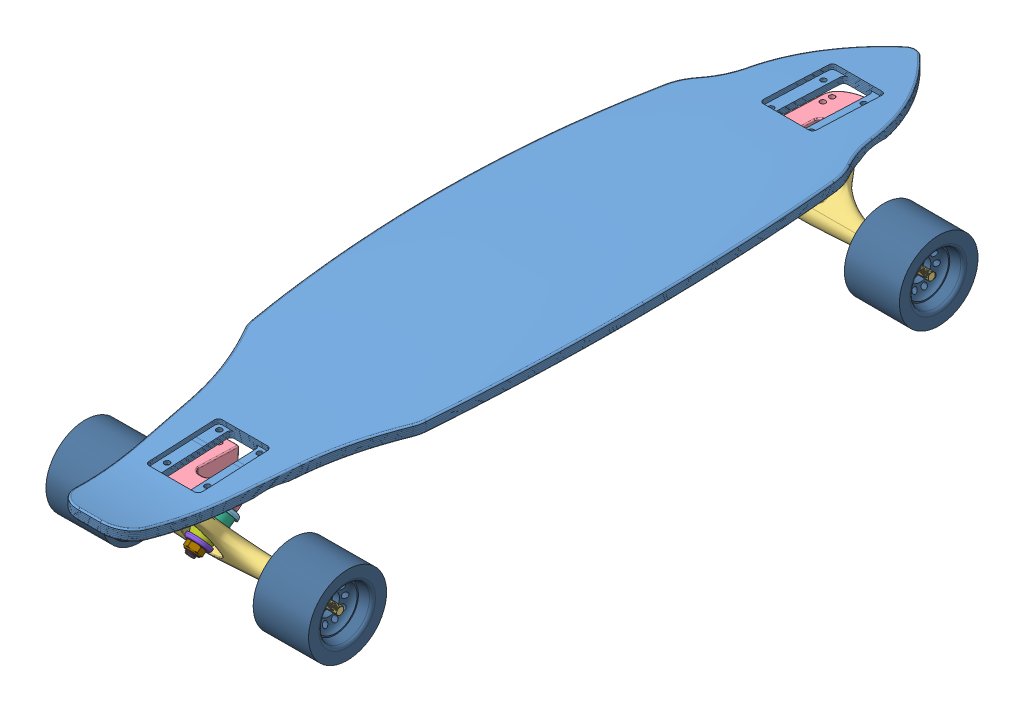
SolidWorks assembly DeckAndTrucks, configuration Default. Lengths in mm.
Overall size (266.41 157.6 846.49).
25 component instances, 11 part files, 25 mates.
Components (placement in the parent):
- Chamber Deck-2: Chamber Deck [Default] at origin size (203.4 42.87 846.49)
- Truck Cutout-1: Truck Cutout [Default] at (0 15.4335 -251.2196) x (-1 0 0) z (0 0.040365 0.999185) size (652.75 200 200) (hidden)
- Truck Cutout-2: Truck Cutout [Default] at (0 12.2172 374.2126) x (1 0 0) z (0 0.044825 -0.998995) size (652.75 200 200) (hidden)
- Truck-2: Truck [Default] at (27.686 -6.6481 -210.3024) x (1 0 0) z (0 -0.0403 -0.999188) size (265.5 107.22 102.66)
  - Rubber Bushing-1: Rubber Bushing [Default] at (-27.686 9.105 71.5015) x (-0.125245 -0.637726 -0.760012) z (0 0.766044 -0.642788) size (17.78 17.78 15.24)
  - Truck Black-1: Truck Black [Default] at (-27.686 18.8338 63.3381) x (1 0 0) z (0 -0.766044 0.642788) size (251.63 24.69 81.31)
  - Truck Silver-1: Truck Silver [Default] at (-27.686 0 0) x (-1 0 0) z (0 0 -1) size (55.37 68.72 102.66)
  - Large Washer-1: Large Washer [Default] at (-27.686 37.0748 22.445) x (1 0 0) z (0 -0.642788 -0.766044) size (29.97 29.97 4.65)
  - Fat Bushing-1: Fat Bushing [Default] at (-27.686 38.3809 24.0016) x (0.983823 -0.137233 0.115152) z (-0.179144 -0.753652 0.632389) size (25.4 13.76 25.4)
  - Small Bushing-1: Small Bushing [Default] at (-27.686 49.674 37.4601) x (0.221595 -0.747 0.626807) z (0 -0.642788 -0.766044) size (25.4 25.4 13.33)
  - Small Washer-1: Small Washer [Default] at (-27.686 59.5517 49.2319) x (0.99468 -0.07891 0.066213) z (0 0.642788 0.766044) size (23.24 23.24 4.15)
  - 3_8 nut-1: 3_8 nut [94945A218] at (-27.686 59.5517 49.2319) x (1 0 0) z (0 -0.766044 0.642788) size (14.29 7.02 16.5)
  - Kegel 80mm longboard wheel-1: Kegel 80mm longboard wheel [Default] at (-123.0988 64.6541 29.035) x (0 -0.998139 0.06098) z (0 0.06098 0.998139) size (80 56 80)
  - Kegel 80mm longboard wheel-2: Kegel 80mm longboard wheel [Default] at (67.7268 64.6541 29.035) x (0 -0.998139 0.06098) z (0 -0.06098 -0.998139) size (80 56 80)
- Truck-4: Truck [Default] at (-28.5015 -3.4029 334.0274) x (-0.999975 0.000286 0.007074) z (0.00708 0.040364 0.99916) size (265.5 107.22 102.66)
  - Rubber Bushing-1: Rubber Bushing [Default] at (-27.686 9.105 71.5015) x (-0.125245 -0.637726 -0.760012) z (0 0.766044 -0.642788) size (17.78 17.78 15.24)
  - Truck Black-1: Truck Black [Default] at (-27.686 18.8338 63.3381) x (1 0 0) z (0 -0.766044 0.642788) size (251.63 24.69 81.31)
  - Truck Silver-1: Truck Silver [Default] at (-27.686 0 0) x (-1 0 0) z (0 0 -1) size (55.37 68.72 102.66)
  - Large Washer-1: Large Washer [Default] at (-27.686 37.0748 22.445) x (1 0 0) z (0 -0.642788 -0.766044) size (29.97 29.97 4.65)
  - Fat Bushing-1: Fat Bushing [Default] at (-27.686 38.3809 24.0016) x (0.983823 -0.137233 0.115152) z (-0.179144 -0.753652 0.632389) size (25.4 13.76 25.4)
  - Small Bushing-1: Small Bushing [Default] at (-27.686 49.674 37.4601) x (0.221595 -0.747 0.626807) z (0 -0.642788 -0.766044) size (25.4 25.4 13.33)
  - Small Washer-1: Small Washer [Default] at (-27.686 59.5517 49.2319) x (0.99468 -0.07891 0.066213) z (0 0.642788 0.766044) size (23.24 23.24 4.15)
  - 3_8 nut-1: 3_8 nut [94945A218] at (-27.686 59.5517 49.2319) x (1 0 0) z (0 -0.766044 0.642788) size (14.29 7.02 16.5)
  - Kegel 80mm longboard wheel-1: Kegel 80mm longboard wheel [Default] at (-123.0988 64.6541 29.035) x (0 -0.998139 0.06098) z (0 0.06098 0.998139) size (80 56 80)
  - Kegel 80mm longboard wheel-2: Kegel 80mm longboard wheel [Default] at (67.7268 64.6541 29.035) x (0 -0.998139 0.06098) z (0 -0.06098 -0.998139) size (80 56 80)
Mates (geometry in assembly coordinates):
- Parallel18: parallel: line of Truck Cutout-1 through (23 16.9371 -214) axis (-1 0 0); plane of assembly through (0 0 0) normal (0 0 1)
- Parallel19: parallel: line of Truck Cutout-1 through (23 16.9371 -214) axis (-1 0 0); plane of assembly
- Coincident57: coincident: plane of Truck Cutout-1 through (0 15.4335 -251.2196) normal (-1 0 0); plane of assembly through (0 0 0) normal (1 0 0)
- Coincident58: coincident: face of Chamber Deck-2; point of Truck Cutout-1
- Coincident59: coincident: face of Chamber Deck-2; point of Truck Cutout-1
- Coincident60: coincident: face of Chamber Deck-2; point of Truck Cutout-1
- Parallel20: parallel: line of Truck Cutout-2 through (-23 13.8869 337) axis (1 0 0); plane of assembly
- Parallel21: parallel: line of Truck Cutout-2 through (-23 13.8869 337) axis (1 0 0); plane of assembly
- Coincident63: coincident: plane of Truck Cutout-2 through (0 12.2172 374.2126) normal (1 0 0); plane of assembly through (0 0 0) normal (1 0 0)
- Coincident64: coincident: face of Chamber Deck-2; point of Truck Cutout-2
- Coincident65: coincident: face of Chamber Deck-2; point of Truck Cutout-2
- Coincident66: coincident: face of Chamber Deck-2; point of Truck Cutout-2
- Distance8: distance = 337 mm: line of Truck Cutout-2 through (-23 13.8869 337) axis (1 0 0); plane of assembly
- Distance9: distance = 214 mm: line of Truck Cutout-1 through (23 16.9371 -214) axis (-1 0 0); plane of assembly
- Coincident69: coincident: circle of Chamber Deck-2; circle of ?
- Coincident70: coincident: plane of Chamber Deck-2 through (27 23.6976 341.4442) normal (-1 0 0); plane of ? through (27 8.5922 336.7624) normal (1 0 0)
- Coincident71: coincident: plane of Chamber Deck-2 through (27 26.7675 -218.4004) normal (-1 0 0); plane of ? through (27 12.141 -213.8062) normal (1 0 0)
- Coincident72: coincident: plane of Chamber Deck-2 through (23 11.9796 -217.803) normal (0 0.999185 -0.040365); plane of ? through (0 10.6374 -251.0259) normal (0 -0.999185 0.040365)
- Concentric1: concentric: cylinder of Chamber Deck-2 through (20.55 1.9221 -219.023) axis (0 0.999185 -0.040365) radius 2.75; cylinder of ? through (20.55 11.914 -219.4267) axis (0 0.999185 -0.040365) radius 2.75
- Coincident73: coincident: point of Chamber Deck-2; plane of ? through (49.9427 5.5224 -278.7071) normal (-0.035443 0.999076 -0.024293)
- Coincident74: coincident: point of Chamber Deck-2; plane of ? through (49.9427 5.5224 -278.7071) normal (-0.035443 0.999076 -0.024293)
- Coincident76: coincident: plane of Truck-2 through (0 -6.6481 -210.3024) normal (1 0 0); plane of assembly through (0 0 0) normal (1 0 0)
- Parallel22: parallel: plane of Chamber Deck-2 through (23 11.9796 -217.803) normal (0 0.999185 -0.040365); plane of Truck-4/Truck Silver-1 through (-0.8162 -3.4108 333.8316) normal (0 0.999185 -0.040365)
- Coincident78: coincident: point of Chamber Deck-2; plane of Truck-4/Truck Silver-1 through (-0.8162 -3.4108 333.8316) normal (0 0.999185 -0.040365)
- Lock1: lock: unknown of Chamber Deck-2; unknown of Truck-2/Truck Silver-1
